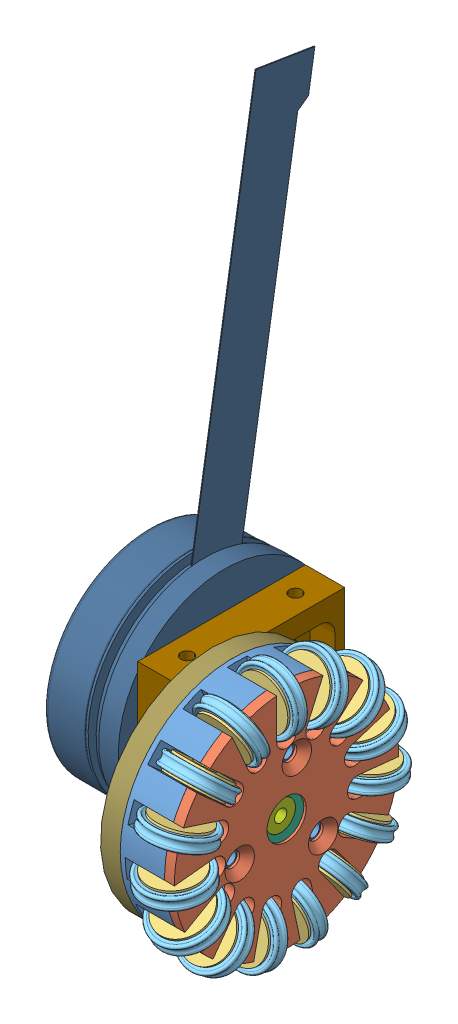
SolidWorks assembly drive_left, configuration Default. Lengths in mm.
Overall size (58.89 137.4 77.93).
70 component instances, 12 part files, 25 mates.
Components (placement in the parent):
- wheel_hub_flat_back-1: wheel_hub_flat_back [Default] at (-31.4027 -2.3485 15.5279) size (9 45.5 45.5)
- wheel_cover-1: wheel_cover [Default] at (-22.4027 -2.3485 15.5279) size (2 45.41 45.5)
- wheel_roller_asm-1: wheel_roller_asm [Default] at (-3.0698 37.2715 -2.2573) x (0.742932 0.669367 0) z (0 0 1) size (12.8 12.8 6)
  - wheel_roller_hub-1: wheel_roller_hub [Default] at (-28.6925 -1.096 17.7852) size (10.4 10.4 3.8)
  - wheel_roller_pin-1: wheel_roller_pin [Default] at (-28.6925 -1.096 14.7852) size (2.5 2.5 6)
  - xring_109-1: xring_109 [Default] at (-28.6925 -1.096 17.7852) size (12.8 12.8 2.6)
- wheel_roller_asm-2: wheel_roller_asm [Default] at (-3.0698 41.0801 15.3952) x (0.742932 0.611497 0.272256) z (0 -0.406737 0.913545) size (12.8 12.8 6)
  - wheel_roller_hub-1: wheel_roller_hub [Default] at (-28.6925 -1.096 17.7852) size (10.4 10.4 3.8)
  - wheel_roller_pin-1: wheel_roller_pin [Default] at (-28.6925 -1.096 14.7852) size (2.5 2.5 6)
  - xring_109-1: xring_109 [Default] at (-28.6925 -1.096 17.7852) size (12.8 12.8 2.6)
- wheel_roller_asm-3: wheel_roller_asm [Default] at (-3.0698 37.3795 33.0707) x (0.742932 0.447894 0.497437) z (0 -0.743145 0.669131) size (12.8 12.8 6)
  - wheel_roller_hub-1: wheel_roller_hub [Default] at (-28.6925 -1.096 17.7852) size (10.4 10.4 3.8)
  - wheel_roller_pin-1: wheel_roller_pin [Default] at (-28.6925 -1.096 14.7852) size (2.5 2.5 6)
  - xring_109-1: xring_109 [Default] at (-28.6925 -1.096 17.7852) size (12.8 12.8 2.6)
- wheel_roller_asm-4: wheel_roller_asm [Default] at (-3.0698 26.8095 47.7129) x (0.742932 0.206846 0.636606) z (0 -0.951057 0.309017) size (12.8 12.8 6)
  - wheel_roller_hub-1: wheel_roller_hub [Default] at (-28.6925 -1.096 17.7852) size (10.4 10.4 3.8)
  - wheel_roller_pin-1: wheel_roller_pin [Default] at (-28.6925 -1.096 14.7852) size (2.5 2.5 6)
  - xring_109-1: xring_109 [Default] at (-28.6925 -1.096 17.7852) size (12.8 12.8 2.6)
- wheel_roller_asm-5: wheel_roller_asm [Default] at (-3.0698 11.1979 56.79) x (0.742932 -0.069968 0.6657) z (0 -0.994522 -0.104528) size (12.8 12.8 6)
  - wheel_roller_hub-1: wheel_roller_hub [Default] at (-28.6925 -1.096 17.7852) size (10.4 10.4 3.8)
  - wheel_roller_pin-1: wheel_roller_pin [Default] at (-28.6925 -1.096 14.7852) size (2.5 2.5 6)
  - xring_109-1: xring_109 [Default] at (-28.6925 -1.096 17.7852) size (12.8 12.8 2.6)
- wheel_roller_asm-6: wheel_roller_asm [Default] at (-3.0698 -6.7561 58.7325) x (0.742932 -0.334684 0.579689) z (0 -0.866025 -0.5) size (12.8 12.8 6)
  - wheel_roller_hub-1: wheel_roller_hub [Default] at (-28.6925 -1.096 17.7852) size (10.4 10.4 3.8)
  - wheel_roller_pin-1: wheel_roller_pin [Default] at (-28.6925 -1.096 14.7852) size (2.5 2.5 6)
  - xring_109-1: xring_109 [Default] at (-28.6925 -1.096 17.7852) size (12.8 12.8 2.6)
- wheel_roller_asm-7: wheel_roller_asm [Default] at (-3.0698 -23.9479 53.2045) x (0.742932 -0.541529 0.393444) z (0 -0.587785 -0.809017) size (12.8 12.8 6)
  - wheel_roller_hub-1: wheel_roller_hub [Default] at (-28.6925 -1.096 17.7852) size (10.4 10.4 3.8)
  - wheel_roller_pin-1: wheel_roller_pin [Default] at (-28.6925 -1.096 14.7852) size (2.5 2.5 6)
  - xring_109-1: xring_109 [Default] at (-28.6925 -1.096 17.7852) size (12.8 12.8 2.6)
- wheel_roller_asm-8: wheel_roller_asm [Default] at (-3.0698 -37.405 41.162) x (0.742932 -0.65474 0.139169) z (0 -0.207912 -0.978148) size (12.8 12.8 6)
  - wheel_roller_hub-1: wheel_roller_hub [Default] at (-28.6925 -1.096 17.7852) size (10.4 10.4 3.8)
  - wheel_roller_pin-1: wheel_roller_pin [Default] at (-28.6925 -1.096 14.7852) size (2.5 2.5 6)
  - xring_109-1: xring_109 [Default] at (-28.6925 -1.096 17.7852) size (12.8 12.8 2.6)
- wheel_roller_asm-9: wheel_roller_asm [Default] at (-3.0698 -44.8005 24.687) x (0.742932 -0.65474 -0.139169) z (0 0.207912 -0.978148) size (12.8 12.8 6)
  - wheel_roller_hub-1: wheel_roller_hub [Default] at (-28.6925 -1.096 17.7852) size (10.4 10.4 3.8)
  - wheel_roller_pin-1: wheel_roller_pin [Default] at (-28.6925 -1.096 14.7852) size (2.5 2.5 6)
  - xring_109-1: xring_109 [Default] at (-28.6925 -1.096 17.7852) size (12.8 12.8 2.6)
- wheel_roller_asm-10: wheel_roller_asm [Default] at (-3.0698 -44.8557 6.6284) x (0.742932 -0.541529 -0.393444) z (0 0.587785 -0.809017) size (12.8 12.8 6)
  - wheel_roller_hub-1: wheel_roller_hub [Default] at (-28.6925 -1.096 17.7852) size (10.4 10.4 3.8)
  - wheel_roller_pin-1: wheel_roller_pin [Default] at (-28.6925 -1.096 14.7852) size (2.5 2.5 6)
  - xring_109-1: xring_109 [Default] at (-28.6925 -1.096 17.7852) size (12.8 12.8 2.6)
- wheel_roller_asm-11: wheel_roller_asm [Default] at (-3.0698 -37.561 -9.8914) x (0.742932 -0.334684 -0.579689) z (0 0.866025 -0.5) size (12.8 12.8 6)
  - wheel_roller_hub-1: wheel_roller_hub [Default] at (-28.6925 -1.096 17.7852) size (10.4 10.4 3.8)
  - wheel_roller_pin-1: wheel_roller_pin [Default] at (-28.6925 -1.096 14.7852) size (2.5 2.5 6)
  - xring_109-1: xring_109 [Default] at (-28.6925 -1.096 17.7852) size (12.8 12.8 2.6)
- wheel_roller_asm-12: wheel_roller_asm [Default] at (-3.0698 -24.1777 -22.016) x (0.742932 -0.069968 -0.6657) z (0 0.994522 -0.104528) size (12.8 12.8 6)
  - wheel_roller_hub-1: wheel_roller_hub [Default] at (-28.6925 -1.096 17.7852) size (10.4 10.4 3.8)
  - wheel_roller_pin-1: wheel_roller_pin [Default] at (-28.6925 -1.096 14.7852) size (2.5 2.5 6)
  - xring_109-1: xring_109 [Default] at (-28.6925 -1.096 17.7852) size (12.8 12.8 2.6)
- wheel_roller_asm-13: wheel_roller_asm [Default] at (-3.0698 -7.02 -27.6489) x (0.742932 0.206846 -0.636606) z (0 0.951057 0.309017) size (12.8 12.8 6)
  - wheel_roller_hub-1: wheel_roller_hub [Default] at (-28.6925 -1.096 17.7852) size (10.4 10.4 3.8)
  - wheel_roller_pin-1: wheel_roller_pin [Default] at (-28.6925 -1.096 14.7852) size (2.5 2.5 6)
  - xring_109-1: xring_109 [Default] at (-28.6925 -1.096 17.7852) size (12.8 12.8 2.6)
- wheel_roller_asm-14: wheel_roller_asm [Default] at (-3.0698 10.9455 -25.8162) x (0.742932 0.447894 -0.497437) z (0 0.743145 0.669131) size (12.8 12.8 6)
  - wheel_roller_hub-1: wheel_roller_hub [Default] at (-28.6925 -1.096 17.7852) size (10.4 10.4 3.8)
  - wheel_roller_pin-1: wheel_roller_pin [Default] at (-28.6925 -1.096 14.7852) size (2.5 2.5 6)
  - xring_109-1: xring_109 [Default] at (-28.6925 -1.096 17.7852) size (12.8 12.8 2.6)
- wheel_roller_asm-15: wheel_roller_asm [Default] at (-3.0698 26.6123 -16.8346) x (0.742932 0.611497 -0.272256) z (0 0.406737 0.913545) size (12.8 12.8 6)
  - wheel_roller_hub-1: wheel_roller_hub [Default] at (-28.6925 -1.096 17.7852) size (10.4 10.4 3.8)
  - wheel_roller_pin-1: wheel_roller_pin [Default] at (-28.6925 -1.096 14.7852) size (2.5 2.5 6)
  - xring_109-1: xring_109 [Default] at (-28.6925 -1.096 17.7852) size (12.8 12.8 2.6)
- MF126ZZ-1: MF126ZZ [Default] at (-21.6027 -2.3485 15.5279) x (-1 0 0) z (0 0.924225 0.381849) size (4 13.6 13.6)
- MF126ZZ-2: MF126ZZ [Default] at (-31.4027 -2.3485 15.5279) size (4 13.6 13.6)
- wheel_rod-1: wheel_rod [Default] at (-21.6027 -2.3485 15.5279) x (-1 0 0) z (0 0.924225 0.381849) size (23 8 8)
- Metric - Spur gear 0.5M 20T 20PA 3FW ---S20O8H8L4N-2: Metric - Spur gear 0.5M 20T 20PA 3FW ---S20O8H8L4N [Metric - Spur gear 0.5M 20T 20PA 3FW ---S20O8H8L4N] at (-35.4027 2.1015 3.8468) x (1 0 0) z (0 0.642462 0.766317) size (8 10.9 10.9)
- motor_mount_left-1: motor_mount_left [Default] at (-44.6027 -15.7485 21.5279) size (8 32 34)
- EC45fl-200142-1: EC45fl-200142 [Default] at (-44.6027 2.1015 3.8468) x (-1 0 0) z (0 0.158938 0.987289) size (46.9 124.1 43.2)
- motor_shaft_extension-1: motor_shaft_extension [Default] at (-55.0027 2.1015 3.8468) x (-1 0 0) z (0 0.167928 -0.985799) size (18.5 4 4)
- DIN - Internal spur gear 0.5M 70T 20PA 4FW ---S70S45,5OD 1AF-1: DIN - Internal spur gear 0.5M 70T 20PA 4FW ---S70S45,5OD 1AF [DIN - Internal spur gear 0.5M 70T 20PA 4FW ---S70S45,5OD 1AF] at (-31.4027 -2.3485 15.5279) x (-1 0 0) z (0 -0.994522 -0.104528) size (4 45.5 45.5)
Mates (geometry in assembly coordinates):
- Width1: width anti-aligned: plane of wheel_hub_flat_back-1 through (-30.4027 12.1015 17.5279) normal (0 0 -1); plane of wheel_hub_flat_back-1 through (-30.4027 20.4015 13.5279) normal (0 0 1); plane of wheel_roller_asm-1/wheel_roller_hub-1 through (-24.5229 18.2173 17.4279) normal (0 0 1); plane of wheel_roller_asm-1/wheel_roller_hub-1 through (-24.9915 18.7374 13.6279) normal (0 0 -1)
- Distance1: distance = 0 mm aligned: plane of wheel_hub_flat_back-1 through (-22.4027 -2.3485 15.5279) normal (1 0 0); cylinder of wheel_roller_asm-1/wheel_roller_pin-1 through (-23.6527 17.2515 18.5279) axis (0 0 -1) radius 1.25
- Distance2: distance = 0 mm anti-aligned: cylinder of wheel_roller_asm-1/wheel_roller_pin-1 through (-23.6527 17.2515 18.5279) axis (0 0 -1) radius 1.25; plane of wheel_hub_flat_back-1 through (-24.9027 18.5015 18.5279) normal (0 -1 0)
- Concentric2: concentric aligned: cylinder of wheel_hub_flat_back-1 through (-22.4027 7.433 13.4488) axis (1 0 0) radius 1.25; cylinder of wheel_cover-1 through (-22.4037 7.433 13.4488) axis (1 0 0) radius 1.5
- Concentric3: concentric aligned: cylinder of wheel_cover-1 through (-22.4037 7.433 13.4488) axis (1 0 0) radius 1.5; cylinder of wheel_hub_flat_back-1 through (-22.4027 7.433 13.4488) axis (1 0 0) radius 1.25
- Coincident1: coincident anti-aligned: plane of wheel_hub_flat_back-1 through (-22.4027 -2.3485 15.5279) normal (1 0 0); plane of wheel_cover-1 through (-22.4027 -2.3485 15.5279) normal (-1 0 0)
- Concentric4: concentric aligned: cylinder of wheel_hub_flat_back-1 through (-22.4027 -2.3485 15.5279) axis (-1 0 0) radius 6.005; cylinder of MF126ZZ-2 through (-31.4027 -2.3485 15.5279) axis (-1 0 0) radius 6
- Coincident2: coincident anti-aligned: plane of wheel_hub_flat_back-1 through (-30.6027 -2.3485 15.5279) normal (-1 0 0); plane of MF126ZZ-2 through (-30.6027 4.4515 15.5279) normal (1 0 0)
- Concentric5: concentric anti-aligned: cylinder of wheel_hub_flat_back-1 through (-22.4027 -2.3485 15.5279) axis (-1 0 0) radius 6.005; cylinder of MF126ZZ-1 through (-21.6027 -2.3485 15.5279) axis (1 0 0) radius 6
- Coincident3: coincident anti-aligned: plane of wheel_hub_flat_back-1 through (-22.4027 -2.3485 15.5279) normal (1 0 0); plane of MF126ZZ-1 through (-22.4027 -4.9451 21.8126) normal (-1 0 0)
- Concentric6: concentric aligned: cylinder of MF126ZZ-1 through (-21.6027 -2.3485 15.5279) axis (1 0 0) radius 3; cylinder of wheel_rod-1 through (-21.6027 -2.3485 15.5279) axis (1 0 0) radius 2.99
- Coincident4: coincident anti-aligned: plane of MF126ZZ-2 through (-31.4027 0.6515 15.5279) normal (-1 0 0); plane of wheel_rod-1 through (-31.4027 -3.8759 19.2248) normal (1 0 0)
- Concentric9: concentric aligned: cylinder of wheel_rod-1 through (-21.6027 -2.3485 15.5279) axis (1 0 0) radius 3; cylinder of motor_mount_left-1 through (-44.6037 -2.3485 15.5279) axis (1 0 0) radius 3
- Concentric10: concentric aligned: cylinder of Metric - Spur gear 0.5M 20T 20PA 3FW ---S20O8H8L4N-2 through (-40.4028 2.1015 3.8468) axis (1 0 0) radius 4; cylinder of motor_mount_left-1 through (-44.6037 2.1015 3.8468) axis (1 0 0) radius 6.1
- Coincident8: coincident anti-aligned: plane of wheel_rod-1 through (-36.6027 -3.4941 18.3006) normal (-1 0 0); plane of motor_mount_left-1 through (-36.6027 -15.7485 21.5279) normal (1 0 0)
- Concentric11: concentric aligned: cylinder of motor_mount_left-1 through (-44.6037 2.1015 3.8468) axis (1 0 0) radius 6.1; cylinder of EC45fl-200142-1 through (-44.6027 2.1015 3.8468) axis (1 0 0) radius 6
- Concentric12: concentric aligned: cylinder of motor_mount_left-1 through (-44.6037 6.0175 -6.4325) axis (1 0 0) radius 1.5; cylinder of EC45fl-200142-1 through (-48.6027 6.0175 -6.4325) axis (1 0 0) radius 1.25
- Coincident9: coincident anti-aligned: plane of motor_mount_left-1 through (-44.6027 -15.7485 21.5279) normal (-1 0 0); plane of EC45fl-200142-1 through (-44.6027 2.1015 3.8468) normal (1 0 0)
- Concentric13: concentric aligned: cylinder of Metric - Spur gear 0.5M 20T 20PA 3FW ---S20O8H8L4N-2 through (-40.4028 2.1015 3.8468) axis (1 0 0) radius 4; cylinder of EC45fl-200142-1 through (-42.1027 2.1015 3.8468) axis (1 0 0) radius 2
- Parallel1: parallel anti-aligned: plane of motor_mount_left-1 through (-36.6027 -15.7485 21.5279) normal (0 -1 0); plane of assembly through (0 0 0) normal (0 1 0)
- Concentric16: concentric: cylinder of EC45fl-200142-1 through (-61.0027 2.1015 3.8468) axis (-1 0 0) radius 1.025; cylinder of motor_shaft_extension-1 through (-73.5027 2.1015 3.8468) axis (-1 0 0) radius 1.25
- Coincident12: coincident anti-aligned: plane of EC45fl-200142-1 through (-61.0027 2.1015 3.8468) normal (-1 0 0); plane of motor_shaft_extension-1 through (-61.0027 3.3337 4.0567) normal (1 0 0)
- Concentric17: concentric anti-aligned: cylinder of wheel_hub_flat_back-1 through (-22.4027 -2.3485 15.5279) axis (-1 0 0) radius 22.75; cylinder of DIN - Internal spur gear 0.5M 70T 20PA 4FW ---S70S45,5OD 1AF-1 through (-21.4027 -2.3485 15.5279) axis (1 0 0) radius 22.75
- Concentric18: concentric: cylinder of wheel_hub_flat_back-1 through (-31.4027 -21.3046 7.0881) axis (-1 0 0) radius 0.8; cylinder of DIN - Internal spur gear 0.5M 70T 20PA 4FW ---S70S45,5OD 1AF-1 through (-31.4017 -21.3046 7.0881) axis (-1 0 0) radius 1
- Coincident13: coincident anti-aligned: plane of wheel_hub_flat_back-1 through (-31.4027 -2.3485 15.5279) normal (-1 0 0); plane of DIN - Internal spur gear 0.5M 70T 20PA 4FW ---S70S45,5OD 1AF-1 through (-31.4027 14.5584 17.3049) normal (1 0 0)
